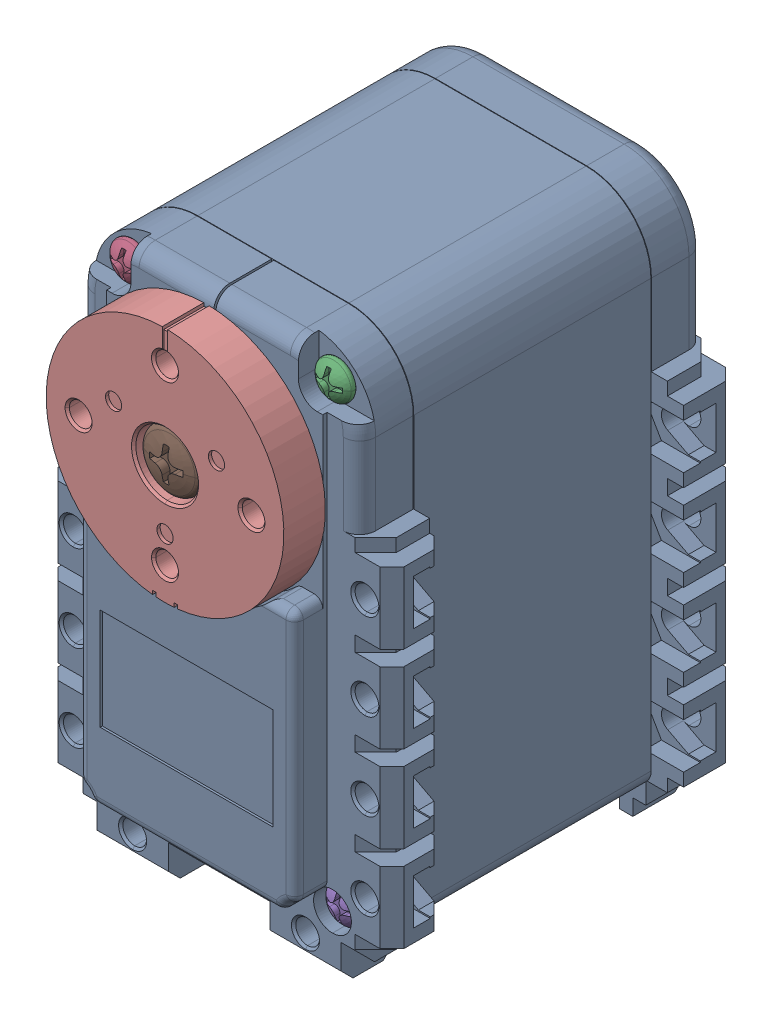
SolidWorks assembly ASM0002_ASM, configuration Default. Lengths in mm.
Overall size (32 50.01 40.05).
11 component instances, 7 part files, 0 mates.
Components (placement in the parent):
- PRT0001-1: PRT0001 [Default] at origin size (32 50.01 38)
- PRT0002-1: PRT0002 [Default] at (0 0 -2) x (-1 0 0) z (0 0 1) size (6.5 6.5 5.5)
- PRT0003-1: PRT0003 [Default] at (9.5 8.5 14.5) x (-1 0 0) z (0 1 0) size (3.5 30.65 3.5)
- PRT0003-2: PRT0003 [Default] at (-9.5 8.5 14.5) x (-1 0 0) z (0 1 0) size (3.5 30.65 3.5)
- PRT0003-3: PRT0003 [Default] at (10.5 -33 14.5) x (-1 0 0) z (0 1 0) size (3.5 30.65 3.5)
- PRT0003-4: PRT0003 [Default] at (-10.5 -33 14.5) x (-1 0 0) z (0 1 0) size (3.5 30.65 3.5)
- PRT0004-1: PRT0004 [Default] at (5.05 -15.19 -9.75) x (1 0 0) z (0 1 0) size (9.9 9.4 4.9)
- PRT0004-2: PRT0004 [Default] at (-4.95 -15.19 -9.75) x (1 0 0) z (0 1 0) size (9.9 9.4 4.9)
- PRT0005-1: PRT0005 [Default] at (0 0 -18.4) x (-1 0 0) z (0 1 0) size (4.98 7 4.98)
- PRT0006-1: PRT0006 [Default] at (0 0 19.16) x (0 1 0) z (0 0 1) size (22 22 6.7)
- PRT0007-1: PRT0007 [Default] at (0 0 19.48) x (-1 0 0) z (0 1 0) size (5.5 9.57 5.5)
